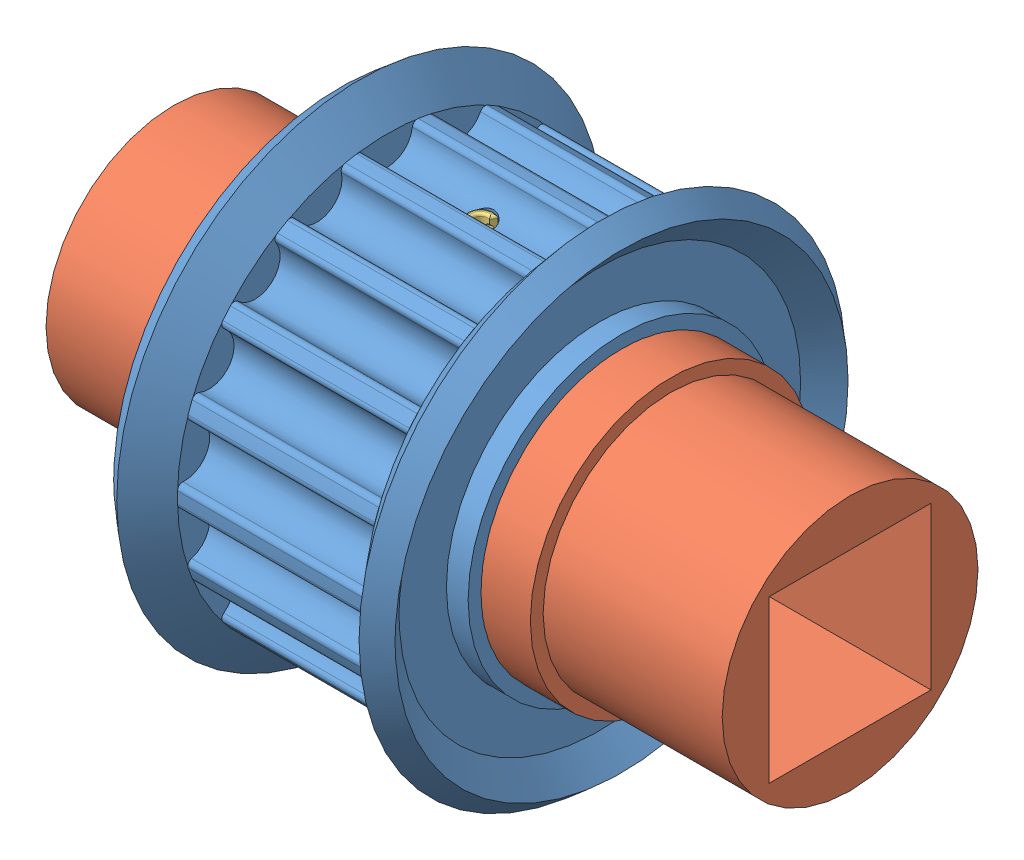
SolidWorks assembly Pulley_MoldedAssmC, configuration Default. Lengths in mm.
Overall size (26.43 19 19).
3 component instances, 3 part files, 5 mates.
Components (placement in the parent):
- GT3x18_GPA18GT3060-A-H8-1: GT3x18_GPA18GT3060-A-H8 [Machined] at origin size (11 19 19)
- Square_Insert-C^Pulley_MoldedAssmC-1: Square_Insert-C^Pulley_MoldedAssmC [Default] at origin size (26.43 11 11) (virtual)
- SpringPin_1x4_91611A065-1: SpringPin_1x4_91611A065 [Default] at (0 5.16 0) x (0 -1 0) z (0.072118 0 0.997396) size (4.02 1.01 1)
Mates (geometry in assembly coordinates):
- Coincident1: coincident aligned: plane of GT3x18_GPA18GT3060-A-H8-1 through (0 0 0) normal (0 0 1); plane of assembly through (0 0 0) normal (0 0 1)
- Coincident2: coincident aligned: plane of GT3x18_GPA18GT3060-A-H8-1 through (0 0 0) normal (0 1 0); plane of assembly through (0 0 0) normal (0 1 0)
- Coincident3: coincident aligned: plane of GT3x18_GPA18GT3060-A-H8-1 through (0 0 0) normal (1 0 0); plane of assembly through (0 0 0) normal (1 0 0)
- Concentric1: concentric anti-aligned: cylinder of GT3x18_GPA18GT3060-A-H8-1 through (0 9.5 0) axis (0 -1 0) radius 0.5; cylinder of SpringPin_1x4_91611A065-1 through (0 5.16 0) axis (0 1 0) radius 0.5
- Coincident4: coincident aligned: plane of ? through (-12 3.16 -3.16) normal (0 -1 0); plane of SpringPin_1x4_91611A065-1 through (0.2181 3.16 -0.4499) normal (0 -1 0)
